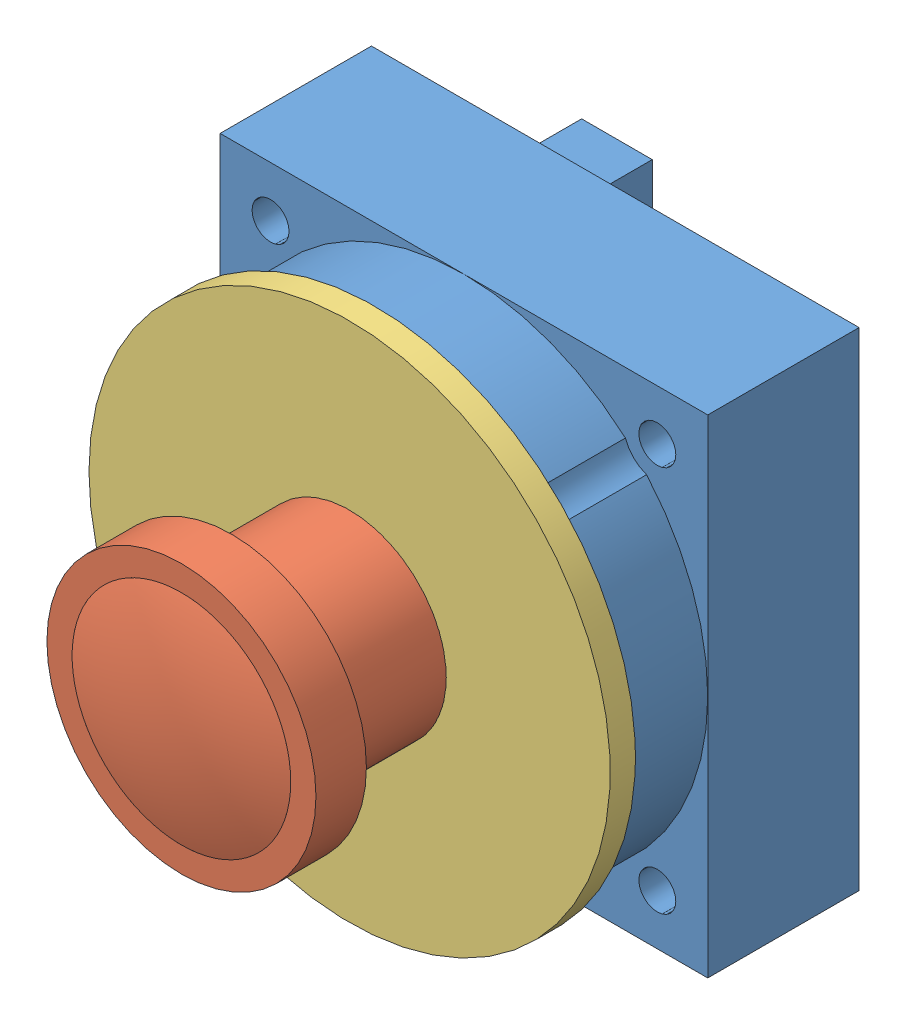
SolidWorks assembly basler_camera_assembly, configuration Default. Lengths in mm.
Overall size (31 31 32.3).
3 component instances, 3 part files, 5 mates.
Components (placement in the parent):
- basler_body-1: basler_body [Default] at origin size (29 29 19.8)
- basler_lens-1: basler_lens [Default] at (14.5 14.5 9) size (16 16 17.8)
- basler_ring-1: basler_ring [Default] at (14.5 14.5 14.3) size (31 31 4.5)
Mates (geometry in assembly coordinates):
- Coincident1: coordinate: point of basler_body-1
- Concentric1: concentric aligned: cylinder of basler_body-1 through (14.5 14.5 8.3) axis (0 0 1) radius 12.6; cylinder of basler_ring-1 through (14.5 14.5 11.3) axis (0 0 1) radius 12.6
- Coincident2: coincident anti-aligned: plane of basler_body-1 through (14.5 14.5 14.3) normal (0 0 1); plane of basler_ring-1 through (14.5 14.5 14.3) normal (0 0 -1)
- Concentric2: concentric aligned: cylinder of basler_lens-1 through (14.5 14.5 22.8) axis (0 0 -1) radius 5.75; cylinder of basler_ring-1 through (14.5 14.5 15.8) axis (0 0 -1) radius 5.75
- Distance1: distance = 7 mm anti-aligned: plane of basler_lens-1 through (14.5 14.5 22.8) normal (0 0 -1); plane of basler_ring-1 through (14.5 14.5 15.8) normal (0 0 1)
